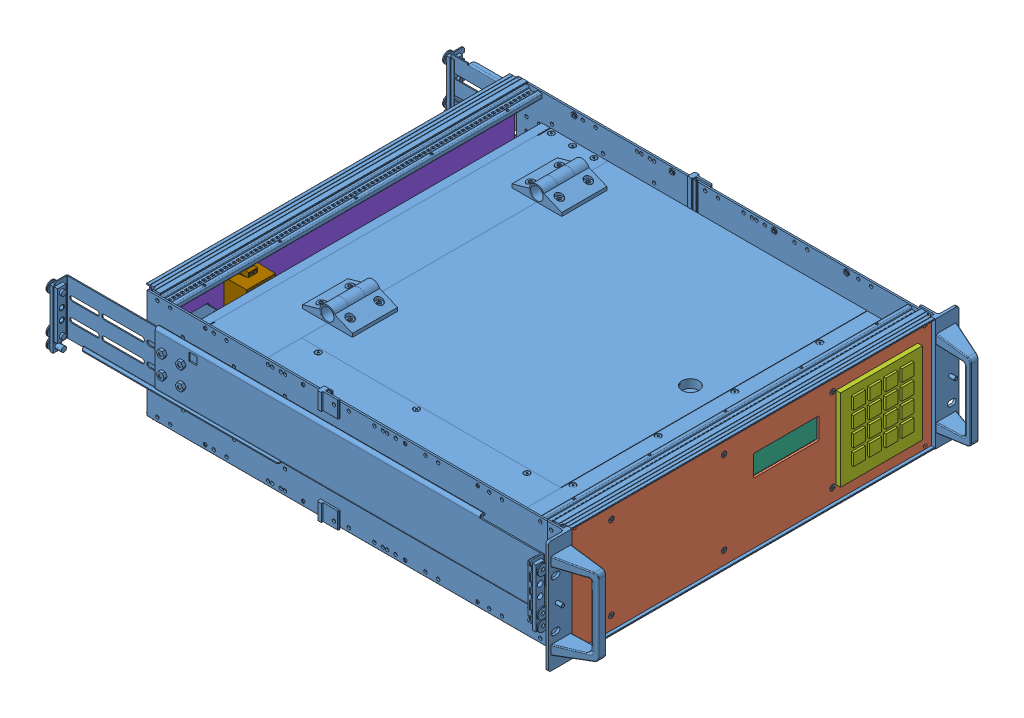
SolidWorks assembly MLA-0387-M4, configuration Default. Lengths in mm.
Overall size (632.74 133.75 484.52).
38 component instances, 13 part files, 6 mates.
Components (placement in the parent):
- HSB COMBI-1: HSB COMBI [Default] at (155.7505 466.3652 694.4069) size (632.74 133.75 484.52)
- MLA-0387-M0-1: MLA-0387-M0 [Default] at (328.6529 624.9353 684.7977) x (0 0 -1) z (0 -1 0) size (426.52 64.16 128.7)
  - MLA-0387-M1-1: MLA-0387-M1 [Default] at (-7.6092 -164.7802 590.2232) size (426.52 2.5 128.7)
  - MLA-0387-P0-PA1-1: MLA-0387-P0-PA1 [Default] at (40.1108 198.8099 361.2232) x (1 0 0) z (0 1 0) size (280 107.5 53.66)
  - pan_head_phillip_M2x4-1: pan_head_phillip_M2x4 [Default] at (204.3608 203.4199 260.2232) x (1 0 0) z (0 0 1) size (4 9.78 4)
  - pan_head_phillip_M2x4-2: pan_head_phillip_M2x4 [Default] at (297.3608 203.4199 260.2232) x (-1 0 0) z (0 0 -1) size (4 9.78 4)
  - pan_head_phillip_M2x4-3: pan_head_phillip_M2x4 [Default] at (204.3608 203.4199 315.2232) x (1 0 0) z (0 0 1) size (4 9.78 4)
  - pan_head_phillip_M2x4-4: pan_head_phillip_M2x4 [Default] at (297.3608 203.4199 315.2232) x (1 0 0) z (0 0 1) size (4 9.78 4)
  - SCREW_ISO 7046-1: SCREW_ISO 7046 [VIJAK M 3x 10] at (45.1108 215.3198 258.7232) x (0 -1 0) z (0 0 1) size (10 5.6 5.6)
  - SCREW_ISO 7046-2: SCREW_ISO 7046 [VIJAK M 3x 10] at (45.1108 215.3198 356.2232) x (0 -1 0) z (-0.86006 0 -0.510193) size (10 5.6 5.6)
  - SCREW_ISO 7046-3: SCREW_ISO 7046 [VIJAK M 3x 10] at (177.6108 215.2333 356.2232) x (0 -1 0) z (0.989385 0 -0.145321) size (10 5.6 5.6)
  - SCREW_ISO 7046-4: SCREW_ISO 7046 [VIJAK M 3x 10] at (177.6108 215.3198 258.7232) x (0 -1 0) z (0.648115 0 0.761542) size (10 5.6 5.6)
  - SCREW_ISO 7046-5: SCREW_ISO 7046 [VIJAK M 3x 10] at (305.1108 215.3198 258.7232) x (0 -1 0) z (0 0 1) size (10 5.6 5.6)
  - SCREW_ISO 7046-6: SCREW_ISO 7046 [VIJAK M 3x 10] at (305.1108 215.3198 356.2232) x (0 -1 0) z (0 0 1) size (10 5.6 5.6)
  - WH2004A1-YYH-3: WH2004A1-YYH [Default] at (201.8608 201.8199 317.7232) x (1 0 0) z (0 1 0) size (98 60 10.6)
  - Storm_7016010-4: Storm_7016010 [Default] at (309.2008 215.3198 355.2732) x (1 0 0) z (0 1 0) size (96 96 22)
- MLA-0387-M2-2: MLA-0387-M2 [Default] at (256.8428 620.1836 246.5299) x (0 0 1) z (0 -1 0) size (426.52 36.95 128.7)
  - MLA-0387-M3-1: MLA-0387-M3 [Default] at (14.077 -174.6299 585.4715) size (426.52 2.5 128.7)
  - ECL15US12-S-1: ECL15US12-S [Default] at (340.987 202.9701 302.5215) x (0 0 -1) z (1 0 0) size (84 26.49 34.5)
  - DC11_0001_001-1: DC11_0001_001 [Default] at (389.437 205.4701 308.5715) x (1 0 0) z (0 1 0) size (44 34 36.95)
  - SCREW_ISO 7046-1: SCREW_ISO 7046 [VIJAK M 3x 10] at (371.437 207.6701 302.5215) x (0 -1 0) z (0 0 1) size (10 5.6 5.6)
  - SCREW_ISO 7046-2: SCREW_ISO 7046 [VIJAK M 3x 10] at (407.437 207.6701 302.5215) x (0 -1 0) z (0 0 1) size (10 5.6 5.6)
  - M3 X 10mm Screw-1: M3 X 10mm Screw [Default] at (328.287 207.8701 340.0215) x (0 -1 0) z (0 0 1) size (12.61 5.6 5.6)
  - M3 X 10mm Screw-2: M3 X 10mm Screw [Default] at (353.687 207.8701 340.2611) x (0 -1 0) z (0 0 1) size (12.61 5.6 5.6)
  - M3 X 10mm Screw-3: M3 X 10mm Screw [Default] at (353.687 207.8701 265.0215) x (0 -1 0) z (0 0 1) size (12.61 5.6 5.6)
  - M3 X 10mm Screw-4: M3 X 10mm Screw [Default] at (328.287 207.8701 265.0215) x (0 -1 0) z (0 0 1) size (12.61 5.6 5.6)
  - M3 screw size FLAT WASHER-1: M3 screw size FLAT WASHER [Default] at (407.437 202.9701 302.5215) x (0.944963 0 -0.327176) z (0 -1 0) size (7 7 0.6)
  - M3 screw size FLAT WASHER-2: M3 screw size FLAT WASHER [Default] at (371.437 202.3701 302.5215) x (1 0 0) z (0 1 0) size (7 7 0.6)
  - M3 x 0.5mm Thread HEX NUT-1: M3 x 0.5mm Thread HEX NUT [Default] at (407.4348 201.1701 302.5562) x (1 0 0) z (0 1 0) size (5.5 6.35 2.6)
  - M3 x 0.5mm Thread HEX NUT-2: M3 x 0.5mm Thread HEX NUT [Default] at (371.4463 201.1701 302.55) x (1 0 0) z (0 1 0) size (5.5 6.35 2.6)
  - M3 screw size FLAT WASHER-3: M3 screw size FLAT WASHER [Default] at (353.687 199.8701 340.2611) x (1 0 0) z (0 1 0) size (7 7 0.6)
  - M3 screw size FLAT WASHER-4: M3 screw size FLAT WASHER [Default] at (328.287 199.8701 340.0215) x (1 0 0) z (0 1 0) size (7 7 0.6)
  - M3 screw size FLAT WASHER-5: M3 screw size FLAT WASHER [Default] at (328.287 200.4701 265.0215) x (1 0 0) z (0 -1 0) size (7 7 0.6)
  - M3 screw size FLAT WASHER-6: M3 screw size FLAT WASHER [Default] at (353.687 200.4701 265.0215) x (1 0 0) z (0 -1 0) size (7 7 0.6)
  - M3 x 0.5mm Thread HEX NUT-3: M3 x 0.5mm Thread HEX NUT [Default] at (328.3059 198.6701 265.0157) x (1 0 0) z (0 -1 0) size (5.5 6.35 2.6)
  - M3 x 0.5mm Thread HEX NUT-4: M3 x 0.5mm Thread HEX NUT [Default] at (353.679 198.6701 264.9262) x (1 0 0) z (0 -1 0) size (5.5 6.35 2.6)
  - M3 x 0.5mm Thread HEX NUT-5: M3 x 0.5mm Thread HEX NUT [Default] at (353.654 198.6701 340.285) x (1 0 0) z (0 1 0) size (5.5 6.35 2.6)
  - M3 x 0.5mm Thread HEX NUT-6: M3 x 0.5mm Thread HEX NUT [Default] at (328.2745 198.6701 340.0301) x (1 0 0) z (0 1 0) size (5.5 6.35 2.6)
Mates (geometry in assembly coordinates):
- Coincident4: coincident anti-aligned: plane of HSB COMBI-1 through (541.4728 372.9121 692.4069) normal (1 0 0); plane of MLA-0387-M0-1/MLA-0387-M1-1 through (541.4728 337.788 684.3265) normal (-1 0 0)
- Parallel1: parallel anti-aligned: plane of HSB COMBI-1 through (546.9728 382.4121 260.6069) normal (0 -1 0); plane of MLA-0387-M0-1/MLA-0387-M1-1 through (541.4728 382.0121 689.7669) normal (0 1 0)
- Concentric1: concentric anti-aligned: cylinder of HSB COMBI-1 through (536.7728 378.9121 682.2469) axis (1 0 0) radius 0.974; cylinder of MLA-0387-M0-1/MLA-0387-M1-1 through (541.4728 378.9121 682.2469) axis (-1 0 0) radius 1.8
- Coincident3: coincident anti-aligned: plane of HSB COMBI-1 through (53.8728 372.9121 260.6069) normal (-1 0 0); plane of MLA-0387-M2-2/MLA-0387-M3-1 through (53.8728 337.788 268.6872) normal (1 0 0)
- Parallel2: parallel anti-aligned: plane of HSB COMBI-1 through (48.3728 382.4121 692.4069) normal (0 -1 0); plane of MLA-0387-M2-2/MLA-0387-M3-1 through (53.8728 382.0121 263.2469) normal (0 1 0)
- Concentric2: concentric aligned: cylinder of HSB COMBI-1 through (58.5728 378.9121 270.7669) axis (1 0 0) radius 0.974; cylinder of MLA-0387-M2-2/MLA-0387-M3-1 through (53.8728 378.9121 270.7669) axis (1 0 0) radius 1.8
